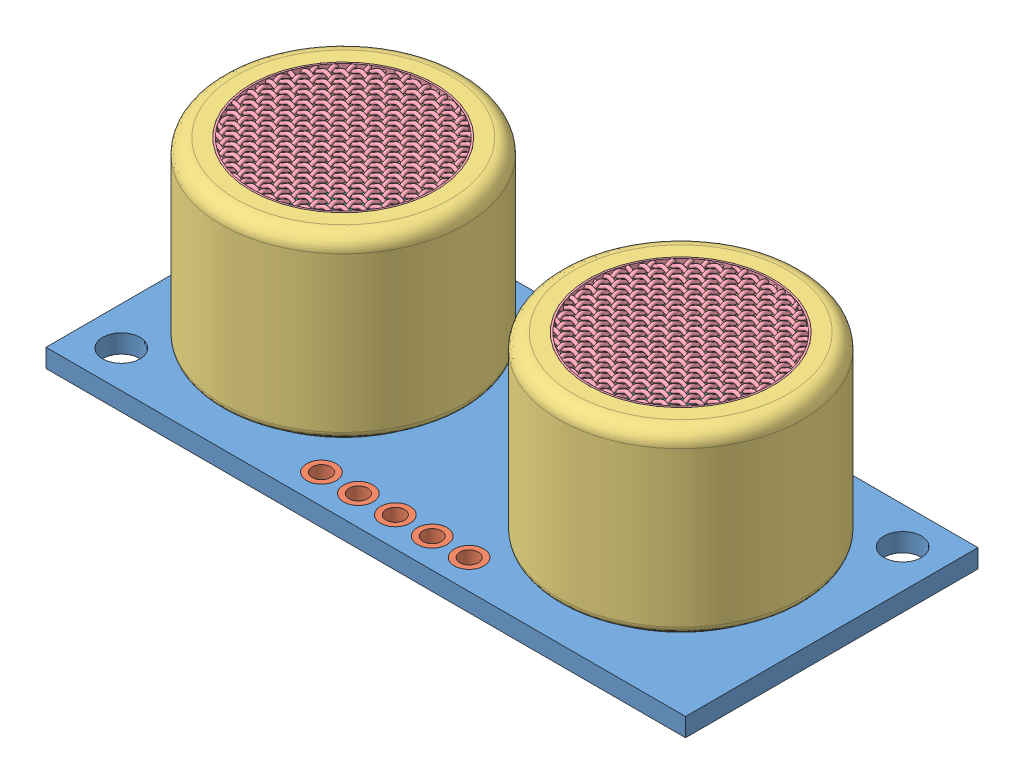
SolidWorks assembly SRF-04, configuration Default. Lengths in mm.
Overall size (43.3 13.85 19.8).
19 component instances, 6 part files, 36 mates.
Components (placement in the parent):
- placa-1: placa [Default] at (1.7512 -0.6465 -0.4849) size (43.3 1.25 19.8)
- pin-1: pin [Default] at (-3.2488 -0.0215 7.4151) size (2 1.25 2)
- pin-3: pin [Default] at (-3.2488 -0.0215 -8.3849) size (2 1.25 2)
- pin-5: pin [Default] at (-0.7488 -0.0215 7.4151) size (2 1.25 2)
- pin-7: pin [Default] at (1.7512 -0.0215 7.4151) size (2 1.25 2)
- pin-9: pin [Default] at (4.2512 -0.0215 7.4151) size (2 1.25 2)
- pin-11: pin [Default] at (6.7512 -0.0215 7.4151) size (2 1.25 2)
- pin-13: pin [Default] at (-0.7488 -0.0215 -8.3849) size (2 1.25 2)
- pin-15: pin [Default] at (1.7512 -0.0215 -8.3849) size (2 1.25 2)
- pin-17: pin [Default] at (4.2512 -0.0215 -8.3849) size (2 1.25 2)
- pin-19: pin [Default] at (6.7512 -0.0215 -8.3849) size (2 1.25 2)
- head-1: head [Default] at (-9.6738 0.6035 -0.4849) x (0.999923 0 -0.012381) z (0.012381 0 0.999923) size (16.5 12.97 16.5)
- head-3: head [Default] at (13.1762 0.6035 -0.4849) x (0.999923 0 -0.012381) z (0.012381 0 0.999923) size (16.5 12.97 16.5)
- rede-1: rede [Default] at (-9.6738 12.5695 -0.4849) size (12.75 0.76 12.75)
- rede-3: rede [Default] at (13.1762 12.5695 -0.4849) size (12.75 0.76 12.75)
- head_1-1: head_1 [Default] at (-9.6738 0.6035 -0.4849) x (0.984488 0 -0.175453) z (0.175453 0 0.984488) size (12.5 5 12.5)
- head_1-3: head_1 [Default] at (13.1762 0.6035 -0.4849) x (0.984488 0 -0.175453) z (0.175453 0 0.984488) size (12.5 5 12.5)
- head_2-1: head_2 [Default] at (-9.6738 4.6035 -0.4849) x (0.995196 0 -0.097899) z (0.097899 0 0.995196) size (9.79 2.15 9.79)
- head_2-3: head_2 [Default] at (13.1762 4.6035 -0.4849) x (0.995196 0 -0.097899) z (0.097899 0 0.995196) size (9.79 2.15 9.79)
Mates (geometry in assembly coordinates):
- Concentric1: concentric aligned: cylinder of placa-1 through (-3.2488 0.6035 7.4151) axis (0 -1 0) radius 1; cylinder of pin-1 through (-3.2488 0.6035 7.4151) axis (0 -1 0) radius 1
- Coincident1: coincident aligned: plane of placa-1 through (-19.8988 0.6035 9.4151) normal (0 1 0); plane of pin-1 through (-3.2488 0.6035 7.4151) normal (0 1 0)
- Concentric2: concentric aligned: cylinder of placa-1 through (-3.2488 0.6035 -8.3849) axis (0 -1 0) radius 1; cylinder of pin-3 through (-3.2488 0.6035 -8.3849) axis (0 -1 0) radius 1
- Coincident2: coincident aligned: plane of placa-1 through (-19.8988 0.6035 9.4151) normal (0 1 0); plane of pin-3 through (-3.2488 0.6035 -8.3849) normal (0 1 0)
- Concentric3: concentric aligned: cylinder of placa-1 through (-0.7488 0.6035 7.4151) axis (0 -1 0) radius 1; cylinder of pin-5 through (-0.7488 0.6035 7.4151) axis (0 -1 0) radius 1
- Coincident3: coincident aligned: plane of placa-1 through (-19.8988 0.6035 9.4151) normal (0 1 0); plane of pin-5 through (-0.7488 0.6035 7.4151) normal (0 1 0)
- Concentric4: concentric aligned: cylinder of placa-1 through (1.7512 0.6035 7.4151) axis (0 -1 0) radius 1; cylinder of pin-7 through (1.7512 0.6035 7.4151) axis (0 -1 0) radius 1
- Coincident4: coincident aligned: plane of placa-1 through (-19.8988 0.6035 9.4151) normal (0 1 0); plane of pin-7 through (1.7512 0.6035 7.4151) normal (0 1 0)
- Concentric5: concentric aligned: cylinder of placa-1 through (4.2512 0.6035 7.4151) axis (0 -1 0) radius 1; cylinder of pin-9 through (4.2512 0.6035 7.4151) axis (0 -1 0) radius 1
- Coincident5: coincident aligned: plane of placa-1 through (-19.8988 0.6035 9.4151) normal (0 1 0); plane of pin-9 through (4.2512 0.6035 7.4151) normal (0 1 0)
- Concentric6: concentric aligned: cylinder of placa-1 through (6.7512 0.6035 7.4151) axis (0 -1 0) radius 1; cylinder of pin-11 through (6.7512 0.6035 7.4151) axis (0 -1 0) radius 1
- Coincident6: coincident aligned: plane of placa-1 through (-19.8988 0.6035 9.4151) normal (0 1 0); plane of pin-11 through (6.7512 0.6035 7.4151) normal (0 1 0)
- Concentric7: concentric aligned: cylinder of placa-1 through (-0.7488 0.6035 -8.3849) axis (0 -1 0) radius 1; cylinder of pin-13 through (-0.7488 0.6035 -8.3849) axis (0 -1 0) radius 1
- Coincident7: coincident aligned: plane of placa-1 through (-19.8988 0.6035 9.4151) normal (0 1 0); plane of pin-13 through (-0.7488 0.6035 -8.3849) normal (0 1 0)
- Concentric8: concentric aligned: cylinder of placa-1 through (1.7512 0.6035 -8.3849) axis (0 -1 0) radius 1; cylinder of pin-15 through (1.7512 0.6035 -8.3849) axis (0 -1 0) radius 1
- Coincident8: coincident aligned: plane of placa-1 through (-19.8988 0.6035 9.4151) normal (0 1 0); plane of pin-15 through (1.7512 0.6035 -8.3849) normal (0 1 0)
- Concentric9: concentric aligned: cylinder of placa-1 through (4.2512 0.6035 -8.3849) axis (0 -1 0) radius 1; cylinder of pin-17 through (4.2512 0.6035 -8.3849) axis (0 -1 0) radius 1
- Coincident9: coincident aligned: plane of placa-1 through (-19.8988 0.6035 9.4151) normal (0 1 0); plane of pin-17 through (4.2512 0.6035 -8.3849) normal (0 1 0)
- Concentric10: concentric aligned: cylinder of placa-1 through (6.7512 0.6035 -8.3849) axis (0 -1 0) radius 1; cylinder of pin-19 through (6.7512 0.6035 -8.3849) axis (0 -1 0) radius 1
- Coincident10: coincident aligned: plane of placa-1 through (-19.8988 0.6035 9.4151) normal (0 1 0); plane of pin-19 through (6.7512 0.6035 -8.3849) normal (0 1 0)
- Concentric11: concentric aligned: cylinder of placa-1 through (-9.6738 0.1035 -0.4849) axis (0 1 0) radius 7.25; cylinder of head-1 through (-9.6738 0.1035 -0.4849) axis (0 1 0) radius 7.25
- Coincident11: coincident anti-aligned: plane of placa-1 through (-9.6738 0.1035 -0.4849) normal (0 1 0); plane of head-1 through (-9.6738 0.1035 -0.4849) normal (0 -1 0)
- Concentric12: concentric aligned: cylinder of placa-1 through (13.1762 0.1035 -0.4849) axis (0 1 0) radius 7.25; cylinder of head-3 through (13.1762 0.1035 -0.4849) axis (0 1 0) radius 7.25
- Coincident12: coincident anti-aligned: plane of placa-1 through (13.1762 0.1035 -0.4849) normal (0 1 0); plane of head-3 through (13.1762 0.1035 -0.4849) normal (0 -1 0)
- Concentric13: concentric aligned: cylinder of head-1 through (-9.6738 12.5695 -0.4849) axis (0 1 0) radius 6.25; cylinder of rede-1 through (-9.6738 12.4399 -0.4849) axis (0 1 0) radius 6.25
- Coincident13: coincident aligned: plane of head-1 through (-9.6738 13.0695 -0.4849) normal (0 1 0); plane of rede-1 through (-16.0488 13.0695 5.8901) normal (0 1 0)
- Concentric14: concentric aligned: cylinder of head-3 through (13.1762 12.5695 -0.4849) axis (0 1 0) radius 6.25; cylinder of rede-3 through (13.1762 12.4399 -0.4849) axis (0 1 0) radius 6.25
- Coincident14: coincident aligned: plane of head-3 through (13.1762 13.0695 -0.4849) normal (0 1 0); plane of rede-3 through (6.8012 13.0695 5.8901) normal (0 1 0)
- Concentric15: concentric aligned: cylinder of head-1 through (-9.6738 13.0695 -0.4849) axis (0 -1 0) radius 7.75; cylinder of head_1-1 through (-9.6738 5.6035 -0.4849) axis (0 -1 0) radius 6.25
- Coincident15: coincident anti-aligned: plane of placa-1 through (-19.8988 0.6035 9.4151) normal (0 1 0); plane of head_1-1 through (-9.6738 0.6035 -0.4849) normal (0 -1 0)
- Concentric16: concentric aligned: cylinder of head-3 through (13.1762 13.0695 -0.4849) axis (0 -1 0) radius 7.75; cylinder of head_1-3 through (13.1762 5.6035 -0.4849) axis (0 -1 0) radius 6.25
- Coincident16: coincident anti-aligned: plane of placa-1 through (-19.8988 0.6035 9.4151) normal (0 1 0); plane of head_1-3 through (13.1762 0.6035 -0.4849) normal (0 -1 0)
- Concentric17: concentric aligned: cylinder of head-1 through (-9.6738 13.0695 -0.4849) axis (0 -1 0) radius 7.75; cylinder of head_2-1 through (-9.6738 4.6035 -0.4849) axis (0 -1 0) radius 1.5
- Coincident17: coincident anti-aligned: plane of head_1-1 through (-9.6738 4.6035 -0.4849) normal (0 1 0); plane of head_2-1 through (-11.1666 4.6035 -0.338) normal (0 -1 0)
- Concentric18: concentric aligned: cylinder of head-3 through (13.1762 13.0695 -0.4849) axis (0 -1 0) radius 7.75; cylinder of head_2-3 through (13.1762 4.6035 -0.4849) axis (0 -1 0) radius 1.5
- Coincident18: coincident anti-aligned: plane of head_1-3 through (13.1762 4.6035 -0.4849) normal (0 1 0); plane of head_2-3 through (11.6834 4.6035 -0.338) normal (0 -1 0)
